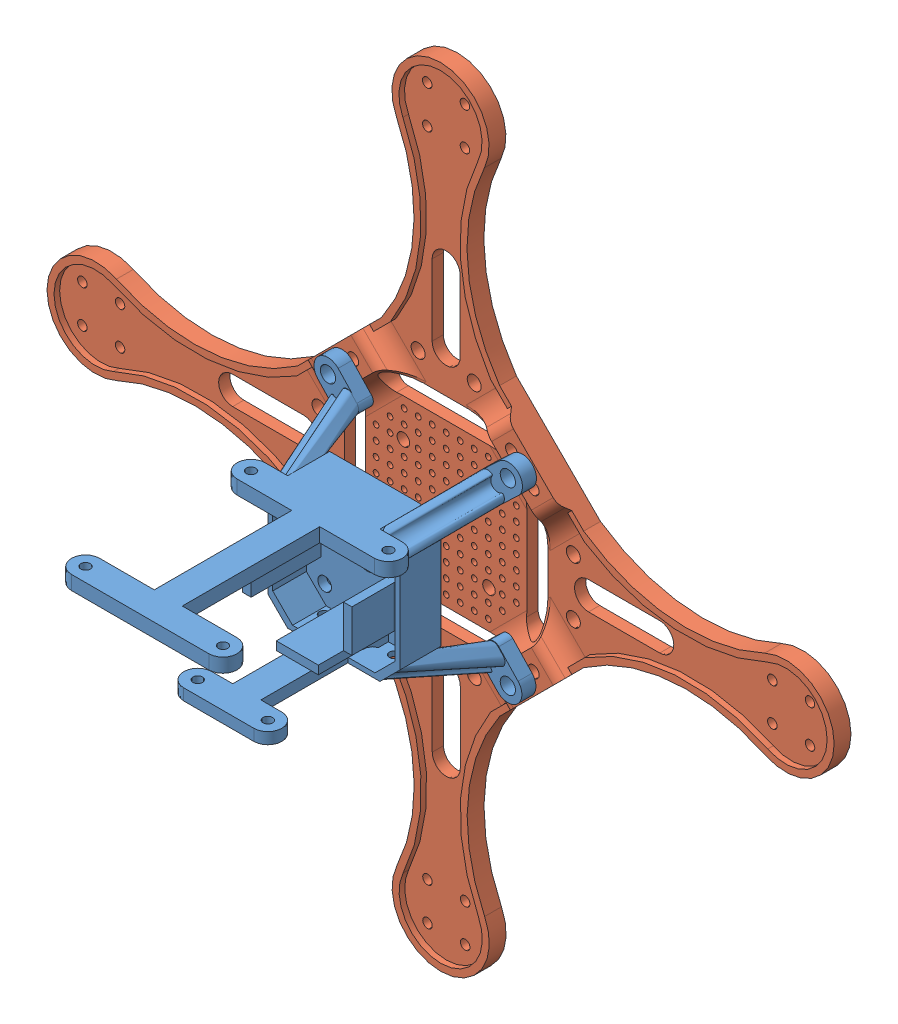
SolidWorks assembly Assem2, configuration Default. Lengths in mm.
Overall size (280.78 280.78 114).
2 component instances, 2 part files, 2 mates.
Components (placement in the parent):
- Superstructure-1: Superstructure [new] at origin size (74.56 74.56 104)
- base plate (Revised holes)-1: base plate (Revised holes) [Default] at (0.086 0.1085 -5) x (1 0.000349 0) z (0 0 -1) size (280.68 280.68 10.27)
Mates (geometry in assembly coordinates):
- Concentric1: concentric aligned: circle of Superstructure-1; circle of base plate (Revised holes)-1
- Coincident3: coincident anti-aligned: plane of Superstructure-1 through (0 0 0) normal (0 0 -1); plane of base plate (Revised holes)-1 through (36.1358 36.1835 0) normal (0 0 1)
